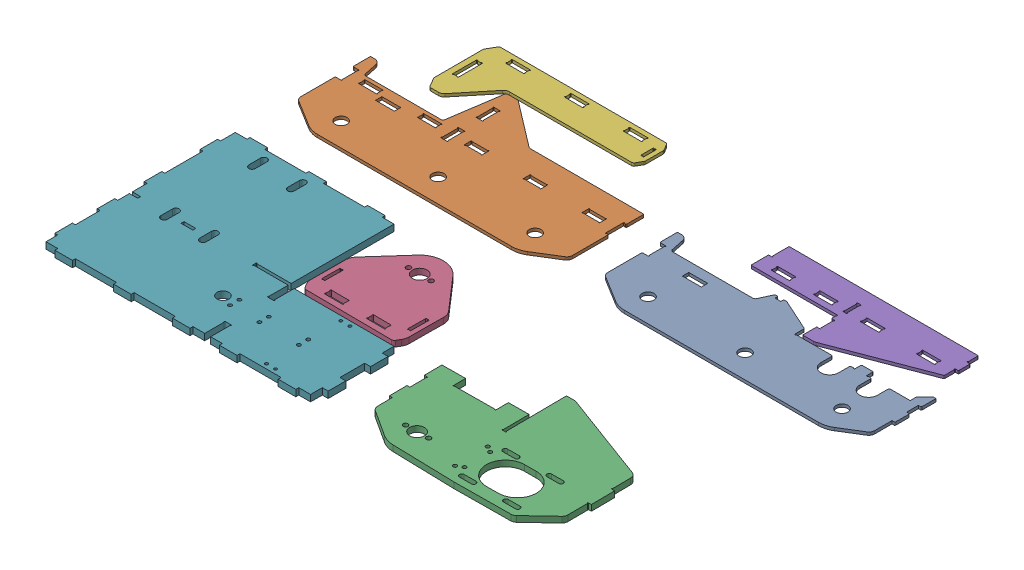
SolidWorks assembly Waterjet Layout, configuration Default. Lengths in mm.
Overall size (626.75 6.99 435.92).
7 component instances, 7 part files, 18 mates.
Components (placement in the parent):
- SMILE Welded Frame_Back Gusset-1: SMILE Welded Frame_Back Gusset [Default] at (432.34 -45.085 -400.05) x (-1 0 0) z (0 -1 0) size (295.28 101.6 3.17)
- SMILE Welded Frame_Front Gusset-1: SMILE Welded Frame_Front Gusset [Default] at (102.14 48.26 -398.78) x (-1 0 0) z (0 -1 0) size (295.28 140.33 3.17)
- SMILE Welded Frame_Inner Rail-1: SMILE Welded Frame_Inner Rail [Default] at (385.0145 -17.875 -31.671) x (0 -1 0) z (-0.999959 0 0.009087) size (6.35 141.4 210.82)
- SMILE Welded Frame_Outer Rail-1: SMILE Welded Frame_Outer Rail [Default] at (239.2557 -90.075 -180.3177) x (0 1 0) z (-0.999973 0 -0.007294) size (6.35 101.6 106.68)
- SMILE Welded Frame_Outer Wall-1: SMILE Welded Frame_Outer Wall [Default] at (454.66 198.85 -447.04) x (0 1 0) z (-1 0 0) size (3.18 75.56 210.82)
- SMILE Welded Frame_Overhang Wall-1: SMILE Welded Frame_Overhang Wall [Default] at (48.418 162.56 -364.49) x (-1 0 0) z (0 1 0) size (192.09 75.56 3.18)
- SMILE Welded Frame_Base Plate-1: SMILE Welded Frame_Base Plate [Default] at (203.295 69.85 -53.34) size (295.28 6.98 210.82)
Mates (geometry in assembly coordinates):
- Coincident1: coincident anti-aligned: plane of SMILE Welded Frame_Back Gusset-1 through (380.365 0 -283.21) normal (0 -1 0)
- Coincident2: coincident anti-aligned: plane of SMILE Welded Frame_Front Gusset-1 through (50.165 0 -284.48) normal (0 -1 0)
- Coincident3: coincident anti-aligned: plane of SMILE Welded Frame_Inner Rail-1 through (385.0145 0 -31.671) normal (0 -1 0)
- Coincident4: coincident anti-aligned: plane of SMILE Welded Frame_Outer Rail-1 through (239.2557 0 -180.3177) normal (0 -1 0)
- Coincident5: coincident anti-aligned: plane of SMILE Welded Frame_Overhang Wall-1 through (48.418 0 -364.49) normal (0 -1 0)
- Coincident6: coincident anti-aligned: plane of SMILE Welded Frame_Outer Wall-1 through (454.66 0 -444.5) normal (0 -1 0)
- Coincident7: coincident anti-aligned: plane of SMILE Welded Frame_Base Plate-1 through (203.295 0 -53.34) normal (0 -1 0)
- Distance1: distance = 5.08 mm: line of SMILE Welded Frame_Base Plate-1
- Distance2: distance = 5.08 mm: plane of SMILE Welded Frame_Base Plate-1 through (299.72 69.85 -53.34) normal (1 0 0)
- Distance3: distance = 5.08 mm: plane of SMILE Welded Frame_Front Gusset-1 through (259.715 0 -259.08) normal (0 0 1)
- Distance4: distance = 3.81 mm: plane of SMILE Welded Frame_Front Gusset-1 through (300.99 97.0004 -322.58) normal (1 0 0)
- Coincident12: coincident aligned: plane of SMILE Welded Frame_Inner Rail-1 through (385.0145 6.35 -31.671) normal (0 1 0); plane of SMILE Welded Frame_Inner Rail-2 through (724.7368 6.35 -135.2137) normal (0 1 0)
- Distance5: distance = 3.175 mm anti-aligned: plane of SMILE Welded Frame_Overhang Wall-1 through (110.743 0 -402.59) normal (0 0 1); plane of SMILE Welded Frame_Front Gusset-1 through (113.665 97.0004 -399.415) normal (0 0 -1)
- Distance6: distance = 3.81 mm: line of SMILE Welded Frame_Front Gusset-1 through (115.8547 0 -399.415) axis (0 1 0); line of SMILE Welded Frame_Overhang Wall-1 through (113.7487 3.175 -402.59) axis (0 -1 0)
- Distance7: distance = 3.175 mm anti-aligned: plane of SMILE Welded Frame_Outer Wall-1 through (512.445 0 -333.375) normal (0 0 1); plane of SMILE Welded Frame_Back Gusset-1 through (628.015 3.175 -330.2) normal (0 0 -1)
- Distance8: distance = 3.81 mm: plane of SMILE Welded Frame_Back Gusset-1 through (631.19 -19.9394 -301.625) normal (1 0 0)
- Distance9: distance = 6.35 mm: plane of SMILE Welded Frame_Back Gusset-1 through (589.915 3.175 -260.35) normal (0 0 1)
- Distance10: distance = 5.08 mm anti-aligned: plane of SMILE Welded Frame_Back Gusset-1 through (494.665 158.8472 -340.36) normal (1 0 0); plane of SMILE Welded Frame_Outer Wall-1 through (499.745 0 -333.375) normal (-1 0 0)
